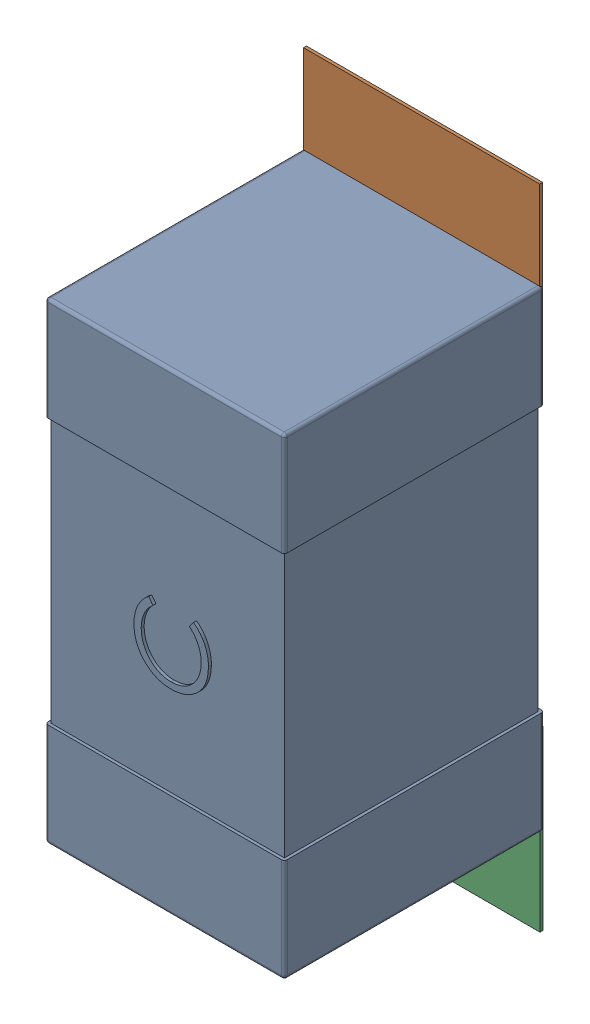
SolidWorks assembly C64, configuration Défaut. Lengths in mm.
Overall size (0.81 2.19 0.88).
5 component instances, 2 part files, 0 mates.
Components (placement in the parent):
- 0603_C-1: 0603_C [Défaut] at (34.9504 -25.9262 0) x (0 1 0) z (0 0 1) size (1.6 0.81 0.88)
- 8260087904-1: 8260087904 [Défaut] at (34.9504 -24.6762 0) size (0.8 0.6 0.01)
  - Extruded_1211-1: Extruded_1211 [Défaut] at origin size (0.8 0.6 0.01)
- 8260087904-2: 8260087904 [Défaut] at (34.9517 -26.2711 0) size (0.8 0.6 0.01)
  - Extruded_1211-1: Extruded_1211 [Défaut] at origin size (0.8 0.6 0.01)
